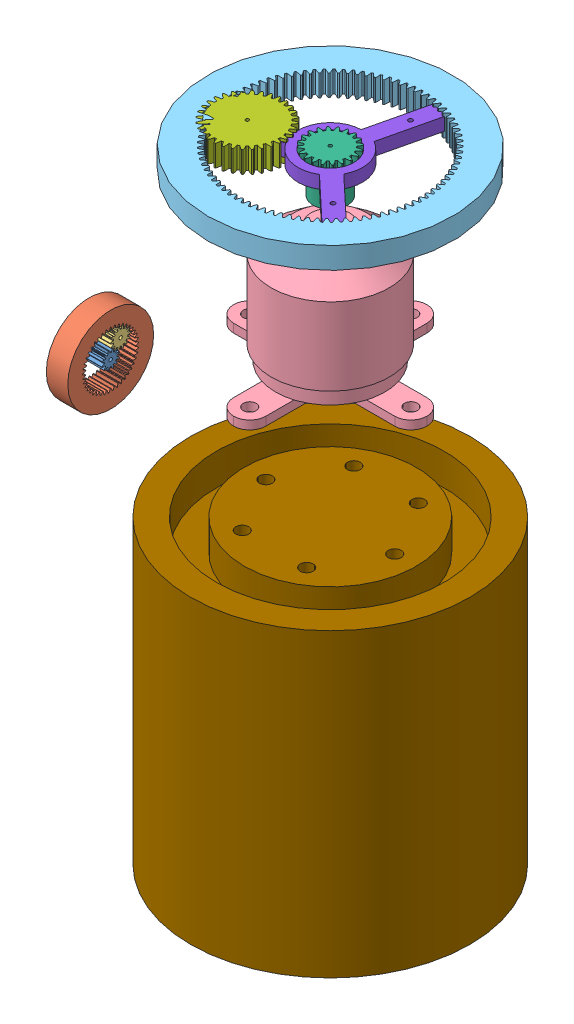
SolidWorks assembly Ensamblaje Planet Gear v2, configuration Predeterminado. Lengths in mm.
Overall size (65 144.81 91.36).
9 component instances, 9 part files, 10 mates.
Components (placement in the parent):
- Sun Gear-1: Sun Gear [ISO - Spur gear 0.3M 12T 20PA 5FW ---S12B2.5H10L0.8N] at (-0.0397 -0.5944 -1.4407) size (10 4.08 4.08)
- Ring gear - ISO - Internal spur gear 0.3M 41T 20PA 5FW-1: Ring gear - ISO - Internal spur gear 0.3M 41T 20PA 5FW [ISO - Internal spur gear 0.3M 41T 20PA 5FW ---S41S20OD 1.0AF] at (-0.0397 -0.5944 -1.4407) size (5 20 20)
- Planet Gear - ISO - Spur gear 0.3M 14T 20PA 5FW-1: Planet Gear - ISO - Spur gear 0.3M 14T 20PA 5FW [ISO - Spur gear 0.3M 14T 20PA 5FW ---S14A75H50L0.8N] at (-0.0397 2.6536 -3.7405) size (5 4.71 4.8)
- brushless A2212-1: brushless A2212 [Predeterminado] at (7.2083 -20.561 -50.3027) size (45 40.5 45)
- Ring Gear - ISO - Internal spur gear 0.5M 85T 20PA 5FW -1: Ring Gear - ISO - Internal spur gear 0.5M 85T 20PA 5FW  [ISO - Internal spur gear 0.5M 85T 20PA 5FW ---S85S57OD 1.0AF] at (7.2083 14.2245 -50.3027) x (0 1 0) z (0 0 1) size (5 57 57)
- Sun Gear - ISO - Spur gear 0.5M 20T 20PA 5FW-1: Sun Gear - ISO - Spur gear 0.5M 20T 20PA 5FW [ISO - Spur gear 0.5M 20T 20PA 5FW ---S20B8H10L0.8N] at (7.2083 14.2245 -50.3027) x (0 1 0) z (-0.970179 0 -0.242389) size (10 10.9 10.9)
- Planet Gear - ISO - Spur gear 0.5M 32T 20PA 5FW-1: Planet Gear - ISO - Spur gear 0.5M 32T 20PA 5FW [ISO - Spur gear 0.5M 32T 20PA 5FW ---S32A75H50L0.8N] at (-7.6348 19.2245 -45.8382) x (0 -1 0) z (0 0 1) size (5 16.94 16.94)
- BaseParaUnirEngranes-1: BaseParaUnirEngranes [Predeterminado] at (7.2083 15.574 -50.3027) x (0.973341 0 0.229361) z (-0.229361 0 0.973341) size (38.59 3 33.42)
- ActuadorSimplificado-1: ActuadorSimplificado [Predeterminado] at (7.2083 -125.5865 -50.3027) size (65 70 65)
Mates (geometry in assembly coordinates):
- Concéntrica7: concentric anti-aligned: circle of Sun Gear-1; circle of Ring gear - ISO - Internal spur gear 0.3M 41T 20PA 5FW-1
- Coincidente1: coincident aligned: plane of Sun Gear-1 through (4.9603 -0.5944 -1.4407) normal (1 0 0); plane of Ring gear - ISO - Internal spur gear 0.3M 41T 20PA 5FW-1 through (4.9603 -0.5944 -7.2907) normal (1 0 0)
- Coincidente2: coincident aligned: plane of Ring gear - ISO - Internal spur gear 0.3M 41T 20PA 5FW-1 through (4.9603 -0.5944 -7.2907) normal (1 0 0); plane of Planet Gear - ISO - Spur gear 0.3M 14T 20PA 5FW-1 through (4.9603 2.6536 -3.7405) normal (1 0 0)
- Concéntrica8: concentric anti-aligned: circle of brushless A2212-1; circle of Ring Gear - ISO - Internal spur gear 0.5M 85T 20PA 5FW -1
- Concéntrica9: concentric anti-aligned: circle of brushless A2212-1; circle of Sun Gear - ISO - Spur gear 0.5M 20T 20PA 5FW-1
- Coincidente3: coincident aligned: plane of Ring Gear - ISO - Internal spur gear 0.5M 85T 20PA 5FW -1 through (7.2083 19.2245 -71.0527) normal (0 1 0); plane of Sun Gear - ISO - Spur gear 0.5M 20T 20PA 5FW-1 through (7.2083 19.2245 -50.3027) normal (0 1 0)
- Coincidente5: coincident aligned: plane of Ring Gear - ISO - Internal spur gear 0.5M 85T 20PA 5FW -1 through (7.2083 19.2245 -71.0527) normal (0 1 0); plane of Planet Gear - ISO - Spur gear 0.5M 32T 20PA 5FW-1 through (-7.6348 19.2245 -45.8382) normal (0 1 0)
- Concéntrica10: concentric aligned: circle of brushless A2212-1; circle of BaseParaUnirEngranes-1
- Concéntrica11: concentric aligned: circle of Planet Gear - ISO - Spur gear 0.5M 32T 20PA 5FW-1; circle of BaseParaUnirEngranes-1
- Concéntrica12: concentric anti-aligned: circle of brushless A2212-1; circle of ActuadorSimplificado-1
